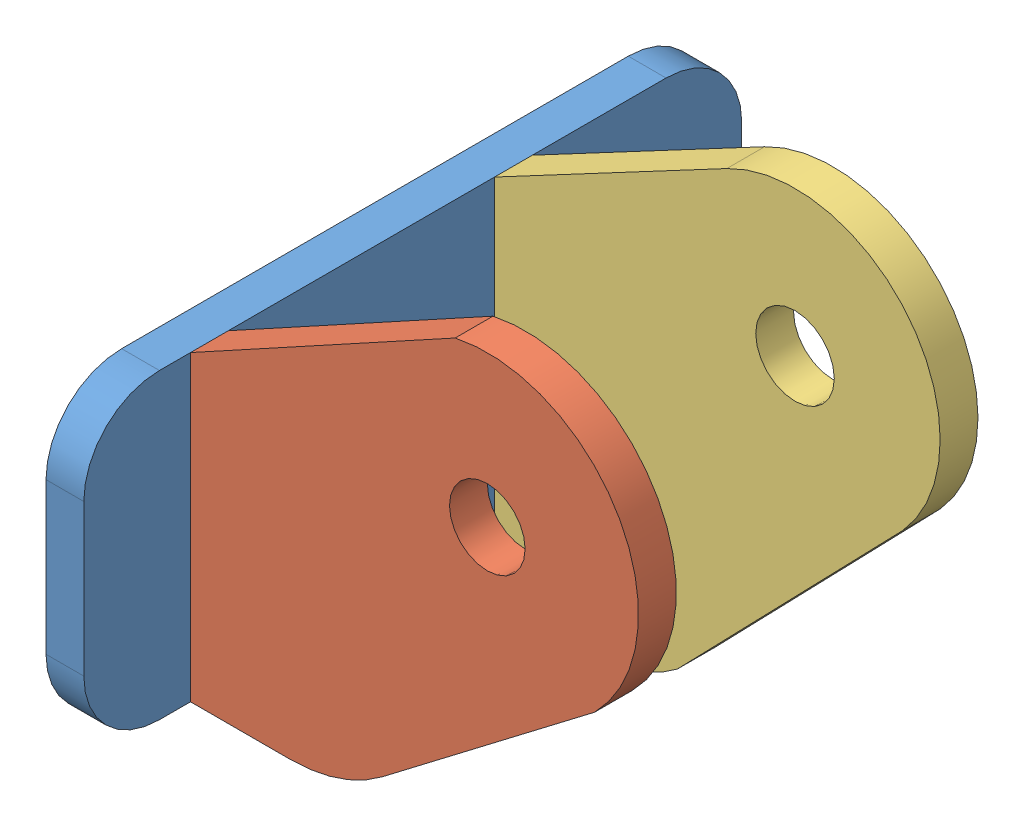
SolidWorks assembly WT-A0100-AB-Toe Bracket, configuration Default. Lengths in mm.
Overall size (40.8 50.39 55.25).
3 component instances, 3 part files, 6 mates.
Components (placement in the parent):
- WT-FB-Toe Base Plate1-1: WT-FB-Toe Base Plate1 [Default] at (22.5935 33.4208 -28.102) size (3.17 37.93 55.25)
- WT-FB-Toe Bottom Clevis1-1: WT-FB-Toe Bottom Clevis1 [Default] at (-402.1509 25.2365 -16.926) x (1 0 0) z (0 0 -1) size (40.8 37.86 3.17)
- WT-GA-Toe Top Clevis1-1: WT-GA-Toe Top Clevis1 [Default] at (102.0031 -4.5841 -39.278) x (1 0 0) z (0 0 -1) size (40.6 42.28 3.17)
Mates (geometry in assembly coordinates):
- Coincident1: coincident anti-aligned: plane of WT-FB-Toe Base Plate1-1 through (25.7685 44.2865 -39.278) normal (0 0 -1); plane of WT-GA-Toe Top Clevis1-1 through (51.0037 50.246 -39.278) normal (0 0 1)
- Coincident3: coincident anti-aligned: plane of WT-FB-Toe Base Plate1-1 through (25.7685 25.4041 -51.9175) normal (1 0 0); plane of WT-GA-Toe Top Clevis1-1 through (25.7685 25.2365 -42.453) normal (-1 0 0)
- Coincident4: coincident aligned: plane of WT-FB-Toe Base Plate1-1 through (22.5935 25.4041 -51.9175) normal (-1 0 0); plane of WT-FB-Toe Bottom Clevis1-1 through (22.5935 47.4615 -13.751) normal (-1 0 0)
- Coincident7: coincident anti-aligned: plane of WT-FB-Toe Base Plate1-1 through (25.7685 44.2865 -42.453) normal (0 -1 0); plane of WT-GA-Toe Top Clevis1-1 through (22.5935 44.2865 -42.453) normal (0 1 0)
- Coincident11: coincident anti-aligned: plane of WT-FB-Toe Base Plate1-1 through (25.7685 47.4615 -16.926) normal (0 0 1); plane of WT-FB-Toe Bottom Clevis1-1 through (50.6923 50.3977 -16.926) normal (0 0 -1)
- Coincident12: coincident anti-aligned: plane of WT-FB-Toe Base Plate1-1 through (25.7685 47.4615 -16.926) normal (0 -1 0); plane of WT-FB-Toe Bottom Clevis1-1 through (25.7685 47.4615 -13.751) normal (0 1 0)
